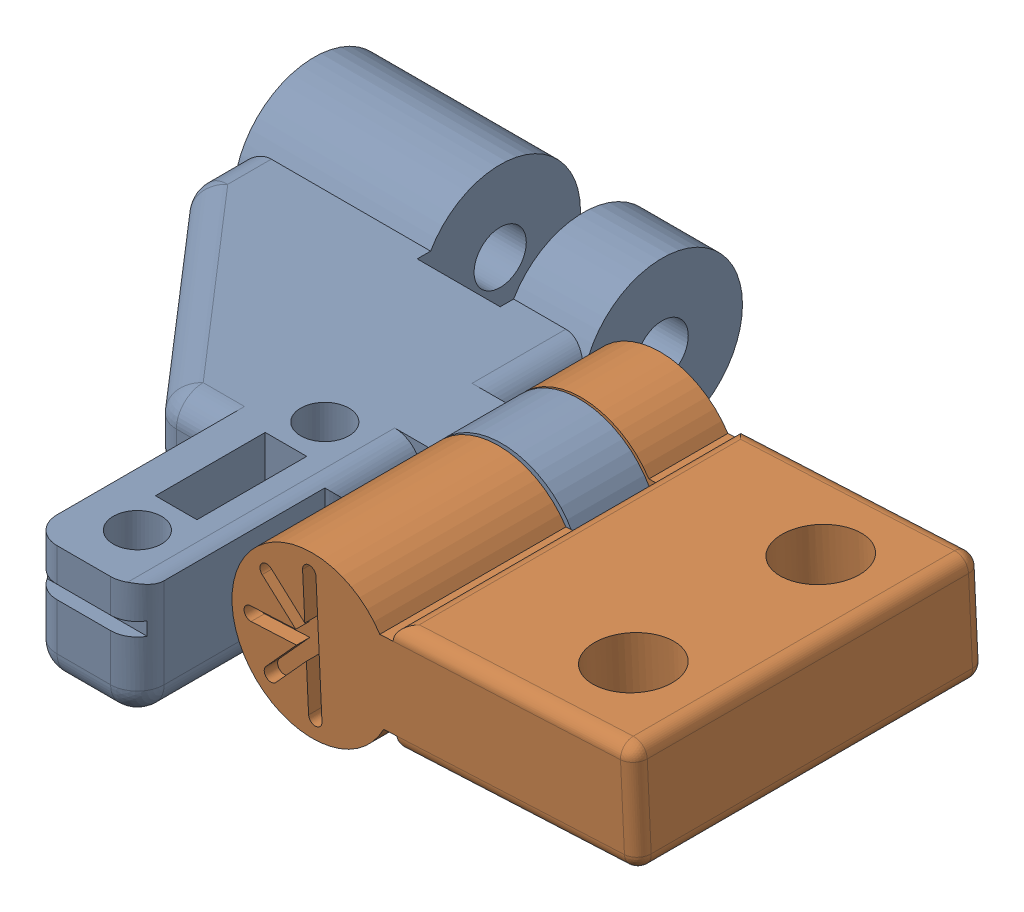
SolidWorks assembly Thumb joint, configuration Default. Lengths in mm.
Overall size (28.23 6.73 22.1).
2 component instances, 2 part files, 1 mates.
Components (placement in the parent):
- thumb mcp abduction joint v4-1: thumb mcp abduction joint v4 [Default] at origin size (19 6 22.1)
- thumb rotation joint v4-1: thumb rotation joint v4 [Default] at (24.1589 0.5935 -0.0318) x (0 0 -1) z (0.998804 0.048899 0) size (13 6 15.1)
Mates (geometry in assembly coordinates):
- Concentric1: concentric aligned: cylinder of thumb mcp abduction joint v4-1 through (12 1.5 0) axis (0 0 -1) radius 1.025; cylinder of thumb rotation joint v4-1 through (12 1.5 2.0682) axis (0 0 -1) radius 0.975
